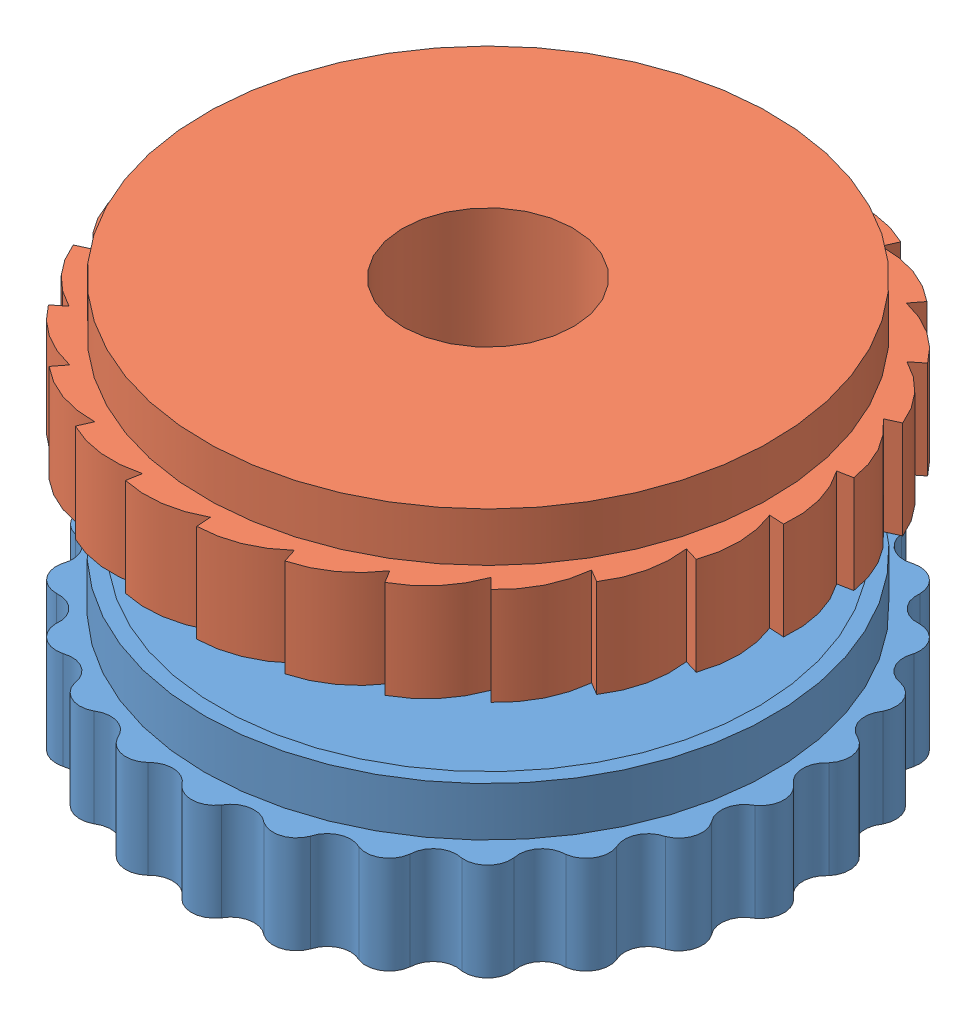
SolidWorks assembly Assem1, configuration Default. Lengths in mm.
Overall size (89.68 39.32 89.71).
2 component instances, 2 part files, 1 mates.
Components (placement in the parent):
- Letter selection wheel-1: Letter selection wheel [Default] at (17.1732 29.2193 55.755) size (64.18 15 64.19)
- Scrambler wheel-1: Scrambler wheel [Default] at (17.1732 53.5424 55.755) x (-0.611568 0 0.791192) z (-0.791192 0 -0.611568) size (64.03 15 63.85)
Mates (geometry in assembly coordinates):
- Coincident1: coincident anti-aligned: circle of Letter selection wheel-1; cylinder of Scrambler wheel-1 through (17.1732 53.5423 55.755) axis (0 1 0) radius 8.7312
